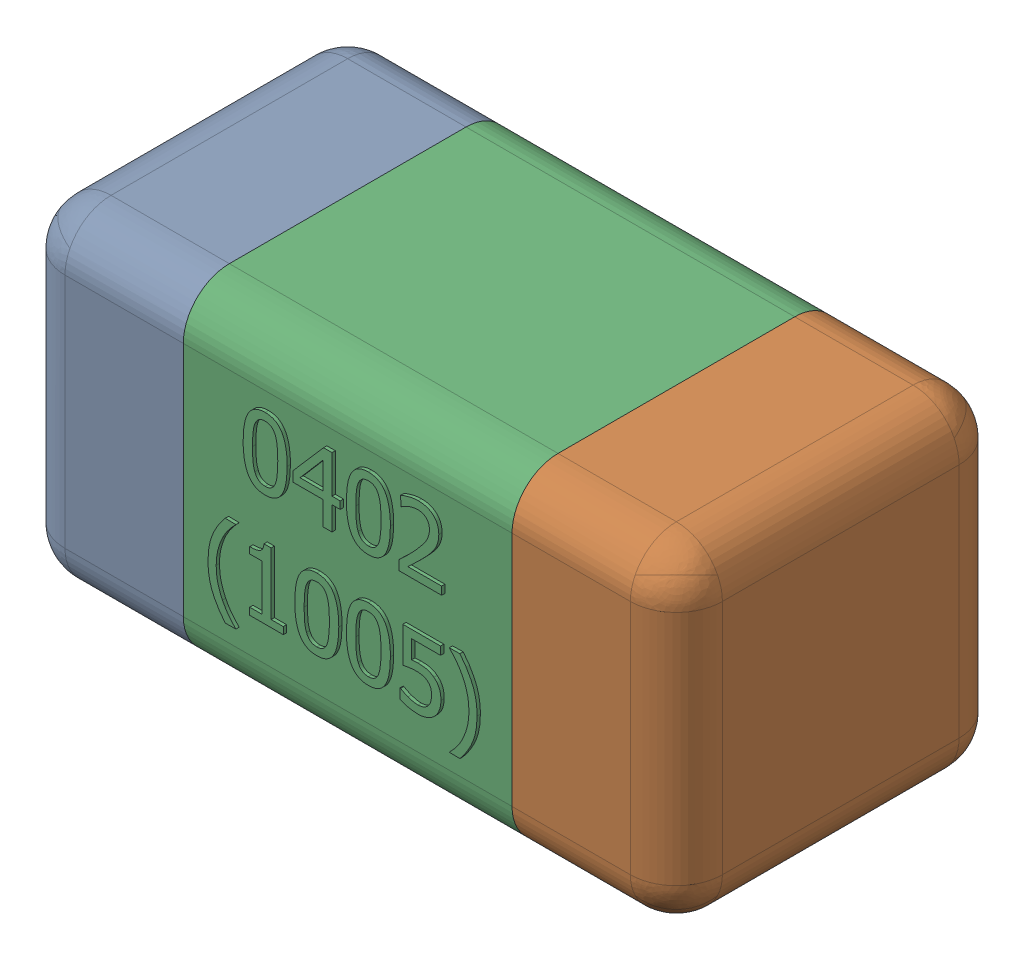
SolidWorks assembly C19, configuration Standard. Lengths in mm.
Overall size (1.01 0.51 0.51).
4 component instances, 3 part files, 0 mates.
Components (placement in the parent):
- C19-subassembly-1-1: C19-subassembly-1 [Standard] at (-3.6999 -8.5 0) x (1 0 0) z (0 0 1) size (1.01 0.51 0.51)
  - User Library-0402_Cap-1: User Library-0402_Cap [Standard] at origin size (0.26 0.51 0.51)
  - User Library-0402_Cap-1-1: User Library-0402_Cap-1 [Standard] at origin size (0.26 0.5 0.51)
  - User Library-0402_Cap-2-1: User Library-0402_Cap-2 [Standard] at origin size (0.5 0.5 0.51)
